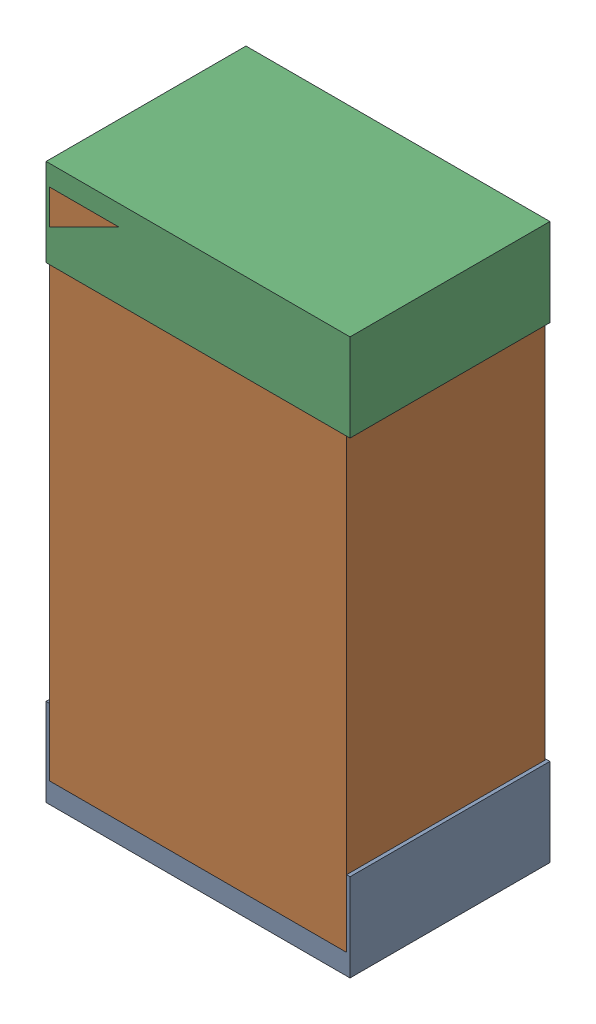
SolidWorks assembly R19Kanaloa_v2.0.0_Motor, configuration Default. Lengths in mm.
Overall size (1.3 2.38 0.85).
6 component instances, 2 part files, 0 mates.
Components (placement in the parent):
- 330415056-1: 330415056 [Default] at (126.238 64.024 -1.9574) size (1.3 0.38 0.85)
  - Extruded_2-1: Extruded_2 [Default] at origin size (1.3 0.38 0.85)
- 334787376-1: 334787376 [Default] at (126.238 65.024 -1.9524) size (1.27 2.2 0.85)
  - Extruded_16-1: Extruded_16 [Default] at origin size (1.27 2.2 0.85)
- 330415056-2: 330415056 [Default] at (126.238 66.024 -1.9574) size (1.3 0.38 0.85)
  - Extruded_2-1: Extruded_2 [Default] at origin size (1.3 0.38 0.85)
